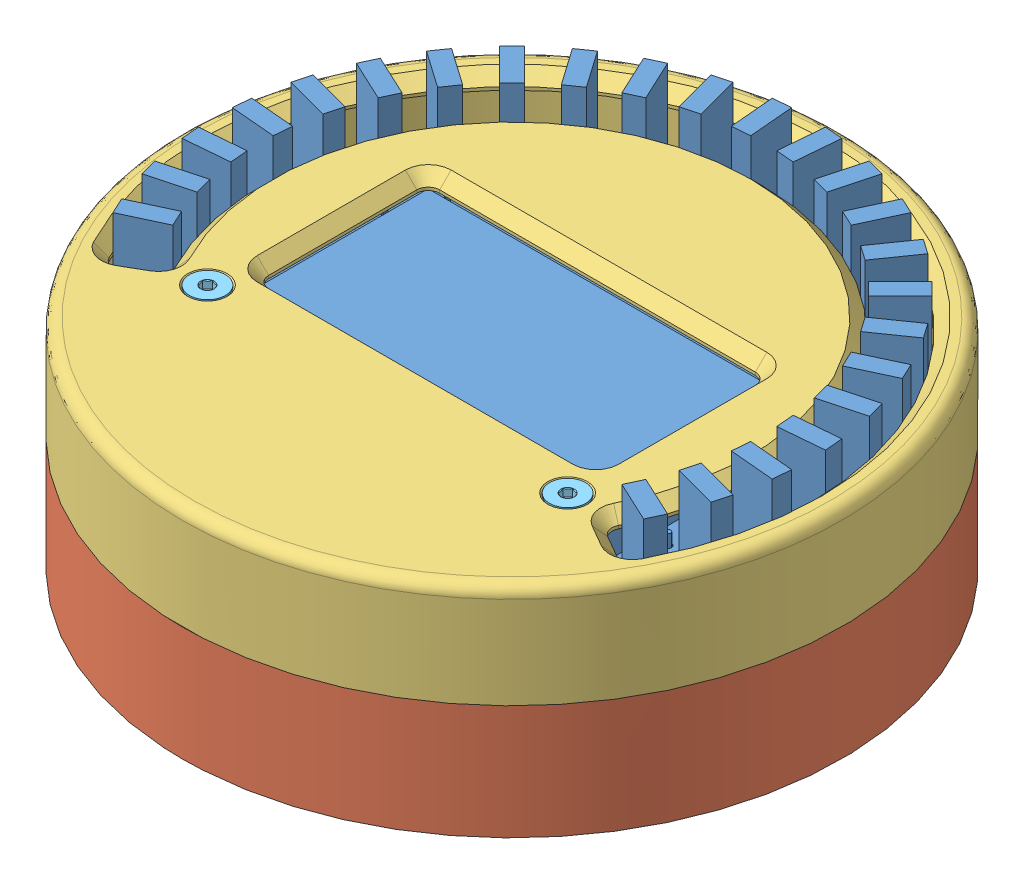
SolidWorks assembly DRO_Housing_Assembly, configuration Default. Lengths in mm.
Overall size (73.19 26.95 73.19).
7 component instances, 5 part files, 15 mates.
Components (placement in the parent):
- DRO_PCB-1: DRO_PCB [Default] at (0 12.7 0) x (1 0 0) z (0 1 0) size (70.54 70.54 16.8)
- DRO_Housing-1: DRO_Housing [Default] at (0 0 -0.0001) size (73.19 12.7 73.19)
- DRO_Housing_Top-1: DRO_Housing_Top [Default] at (0 22.6058 -0.0001) size (73.19 11.51 73.19)
- 94180A307_HEAT-SET INSERTS FOR PLASTICS-1: 94180A307_HEAT-SET INSERTS FOR PLASTICS [Default] at (-20 12.7 13.82) x (0.986698 0 0.162567) z (-0.162567 0 0.986698) size (3.58 3.11 3.58)
- 94180A307_HEAT-SET INSERTS FOR PLASTICS-2: 94180A307_HEAT-SET INSERTS FOR PLASTICS [Default] at (20 12.7 13.82) x (0.986698 0 0.162567) z (-0.162567 0 0.986698) size (3.58 3.11 3.58)
- 91294A539_BLACK ALLOY STEEL FLAT-HEAD SOCKET CAP SCREW-1: 91294A539_BLACK ALLOY STEEL FLAT-HEAD SOCKET CAP SCREW [91294A539] at (-20 24.2058 13.82) x (0.968702 0 -0.248226) z (0 1 0) size (4 4 20.3)
- 91294A539_BLACK ALLOY STEEL FLAT-HEAD SOCKET CAP SCREW-2: 91294A539_BLACK ALLOY STEEL FLAT-HEAD SOCKET CAP SCREW [91294A539] at (20 24.2058 13.82) x (0.968702 0 -0.248226) z (0 1 0) size (4 4 20.3)
Mates (geometry in assembly coordinates):
- Concentric3: concentric aligned: cylinder of DRO_PCB-1 through (-20 11.9 13.82) axis (0 1 0) radius 1.6; cylinder of DRO_Housing-1 through (-20 0 13.82) axis (0 1 0) radius 1.5
- Concentric4: concentric aligned: cylinder of DRO_PCB-1 through (20 11.9 13.82) axis (0 1 0) radius 1.6; cylinder of DRO_Housing-1 through (20 0 13.82) axis (0 1 0) radius 1.5
- Concentric5: concentric aligned: cylinder of DRO_PCB-1 through (-20 11.9 13.82) axis (0 1 0) radius 1.6; cylinder of DRO_Housing_Top-1 through (-20 24.2058 13.82) axis (0 1 0) radius 1.2
- Concentric6: concentric aligned: cylinder of DRO_PCB-1 through (20 11.9 13.82) axis (0 1 0) radius 1.6; cylinder of DRO_Housing_Top-1 through (20 24.2058 13.82) axis (0 1 0) radius 1.2
- Coincident5: coincident anti-aligned: plane of DRO_PCB-1 through (0 14.3 0) normal (0 1 0); plane of DRO_Housing_Top-1 through (0 14.3 -0.0001) normal (0 -1 0)
- Concentric7: concentric aligned: cylinder of DRO_Housing-1 through (-20 0 13.82) axis (0 1 0) radius 1.5; cylinder of 94180A307_HEAT-SET INSERTS FOR PLASTICS-1 through (-20 12.7 13.82) axis (0 1 0) radius 1.482
- Coincident6: coincident aligned: plane of DRO_Housing-1 through (0 12.7 -0.0001) normal (0 1 0); plane of 94180A307_HEAT-SET INSERTS FOR PLASTICS-1 through (-21.7662 12.7 13.529) normal (0 1 0)
- Concentric81: concentric anti-aligned: cylinder of DRO_Housing-1 through (20 0 13.82) axis (0 1 0) radius 1.5; cone of 94180A307_HEAT-SET INSERTS FOR PLASTICS-2 through (20 12.65 13.82) axis (0 -1 0)
- Coincident9: coincident aligned: plane of DRO_Housing-1 through (0 12.7 -0.0001) normal (0 1 0); plane of 94180A307_HEAT-SET INSERTS FOR PLASTICS-2 through (18.2338 12.7 13.529) normal (0 1 0)
- Coincident10: coincident aligned: cone of DRO_Housing_Top-1 through (-20 24.2058 13.82) axis (0 -1 0); cone of 91294A539_BLACK ALLOY STEEL FLAT-HEAD SOCKET CAP SCREW-1 through (-20 23.0058 13.82) axis (0 -1 0)
- Coincident11: coincident aligned: cone of DRO_Housing_Top-1 through (20 24.2058 13.82) axis (0 -1 0); cone of 91294A539_BLACK ALLOY STEEL FLAT-HEAD SOCKET CAP SCREW-2 through (20 23.0058 13.82) axis (0 -1 0)
- Coincident12: coincident anti-aligned: plane of DRO_Housing-1 through (0 0 -0.0001) normal (0 -1 0)
- Coincident13: coincident aligned: plane of DRO_PCB-1 through (0 12.7 0) normal (1 0 0)
- Coincident14: coincident anti-aligned: plane of DRO_PCB-1 through (0 12.7 0) normal (0 0 -1)
- Coincident15: coincident anti-aligned: plane of DRO_PCB-1 through (0 12.7 0) normal (0 -1 0); plane of DRO_Housing-1 through (0 12.7 -0.0001) normal (0 1 0)
